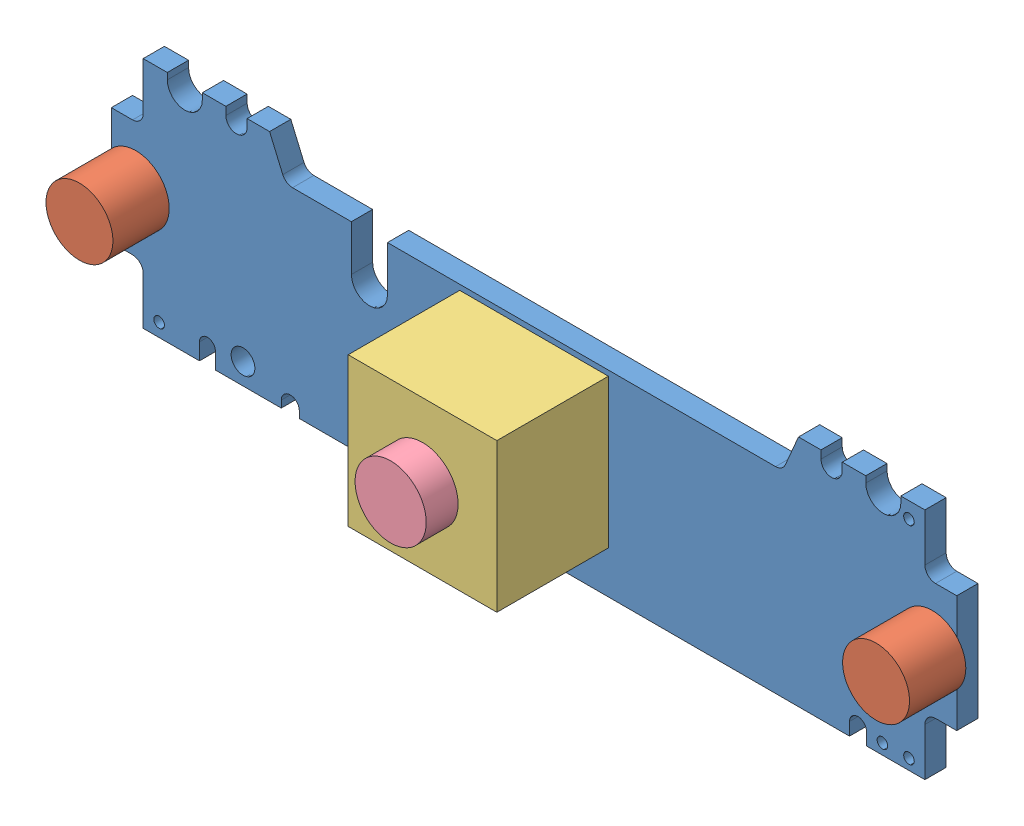
SolidWorks assembly PCB_and_lens, configuration Predeterminado. Lengths in mm.
Overall size (81.3 22 15.5).
5 component instances, 4 part files, 16 mates.
Components (placement in the parent):
- PCB^PCB_and_lens-1: PCB^PCB_and_lens [Predeterminado] at origin size (79.6 22 2) (virtual)
- Speaker^PCB_and_lens-1: Speaker^PCB_and_lens [Predeterminado] at (0 0 2) size (6.3 6.3 5.3) (virtual)
- Speaker^PCB_and_lens-3: Speaker^PCB_and_lens [Predeterminado] at (75 0 2) size (6.3 6.3 5.3) (virtual)
- Lens Mount^PCB_and_lens-1: Lens Mount^PCB_and_lens [Predeterminado] at (0 0 2) size (14 14 10.5) (virtual)
- Pieza4^PCB_and_lens-1: Pieza4^PCB_and_lens [Predeterminado] at (0 0 12.5) size (6.7 6.7 3) (virtual)
Mates (geometry in assembly coordinates):
- EnPosición1: in place: plane of PCB^PCB_and_lens-1 through (0 0 0) normal (0 0 1); moOrthogonalPlaneRef_w of PCB^PCB_and_lens-1 through (0 0 0) normal (0 1 0); plane of PCB^PCB_and_lens-1 through (0 0 0) normal (1 0 0); unknown of PCB^PCB_and_lens-1
- Coincidente1: coincident aligned: plane of PCB^PCB_and_lens-1; plane of assembly
- Coincidente2: coincident aligned: plane of PCB^PCB_and_lens-1 through (0 0 0) normal (0 1 0); moOrthogonalPlaneRef_w of assembly
- Coincidente3: coincident anti-aligned: plane of PCB^PCB_and_lens-1 through (0 0 0) normal (1 0 0); moOrthogonalPlaneRef_w of assembly
- EnPosición2: in place: plane of PCB^PCB_and_lens-1 through (-27.8516 23.0934 2) normal (0 0 1); plane of ? through (0 0 2) normal (0 0 1); plane of PCB^PCB_and_lens-1 through (-27.8516 23.0934 2) normal (0 0 1); plane of ? through (0 0 2) normal (0 1 0); plane of PCB^PCB_and_lens-1 through (-27.8516 23.0934 2) normal (0 0 1); plane of ? through (0 0 2) normal (1 0 0); plane of PCB^PCB_and_lens-1 through (-27.8516 23.0934 2) normal (0 0 1); unknown of ?
- Coincidente4: coincident aligned: plane of PCB^PCB_and_lens-1; plane of Speaker^PCB_and_lens-1
- Coincidente5: coincident aligned: moOrthogonalPlaneRef_w of PCB^PCB_and_lens-1 through (0 0 2) normal (0 1 0); plane of Speaker^PCB_and_lens-1 through (0 0 2) normal (0 1 0)
- Coincidente6: coincident anti-aligned: moOrthogonalPlaneRef_w of PCB^PCB_and_lens-1 through (0 0 2) normal (-1 0 0); plane of Speaker^PCB_and_lens-1 through (0 0 2) normal (1 0 0)
- EnPosición3: in place: plane of PCB^PCB_and_lens-1 through (-27.8516 23.0934 2) normal (0 0 1); plane of ? through (0 0 2) normal (0 0 1); plane of PCB^PCB_and_lens-1 through (-27.8516 23.0934 2) normal (0 0 1); plane of ? through (0 0 2) normal (0 1 0); plane of PCB^PCB_and_lens-1 through (-27.8516 23.0934 2) normal (0 0 1); plane of ? through (0 0 2) normal (1 0 0); plane of PCB^PCB_and_lens-1 through (-27.8516 23.0934 2) normal (0 0 1); unknown of ?
- Coincidente7: coincident aligned: plane of PCB^PCB_and_lens-1; plane of Lens Mount^PCB_and_lens-1
- Coincidente8: coincident aligned: moOrthogonalPlaneRef_w of PCB^PCB_and_lens-1 through (0 0 2) normal (0 1 0); plane of Lens Mount^PCB_and_lens-1 through (0 0 2) normal (0 1 0)
- Coincidente9: coincident anti-aligned: moOrthogonalPlaneRef_w of PCB^PCB_and_lens-1 through (0 0 2) normal (-1 0 0); plane of Lens Mount^PCB_and_lens-1 through (0 0 2) normal (1 0 0)
- EnPosición4: in place: plane of ? through (0 0 12.5) normal (0 0 1); plane of Pieza4^PCB_and_lens-1 through (0 0 12.5) normal (0 0 1); plane of ? through (0 0 12.5) normal (0 0 1); plane of Pieza4^PCB_and_lens-1 through (0 0 12.5) normal (0 1 0); plane of ? through (0 0 12.5) normal (0 0 1); plane of Pieza4^PCB_and_lens-1 through (0 0 12.5) normal (1 0 0); plane of ? through (0 0 12.5) normal (0 0 1); unknown of Pieza4^PCB_and_lens-1
- Coincidente10: coincident aligned: plane of Lens Mount^PCB_and_lens-1; plane of Pieza4^PCB_and_lens-1
- Coincidente11: coincident aligned: moOrthogonalPlaneRef_w of Lens Mount^PCB_and_lens-1 through (0 0 12.5) normal (0 1 0); plane of Pieza4^PCB_and_lens-1 through (0 0 12.5) normal (0 1 0)
- Coincidente12: coincident anti-aligned: moOrthogonalPlaneRef_w of Lens Mount^PCB_and_lens-1 through (0 0 12.5) normal (-1 0 0); plane of Pieza4^PCB_and_lens-1 through (0 0 12.5) normal (1 0 0)
